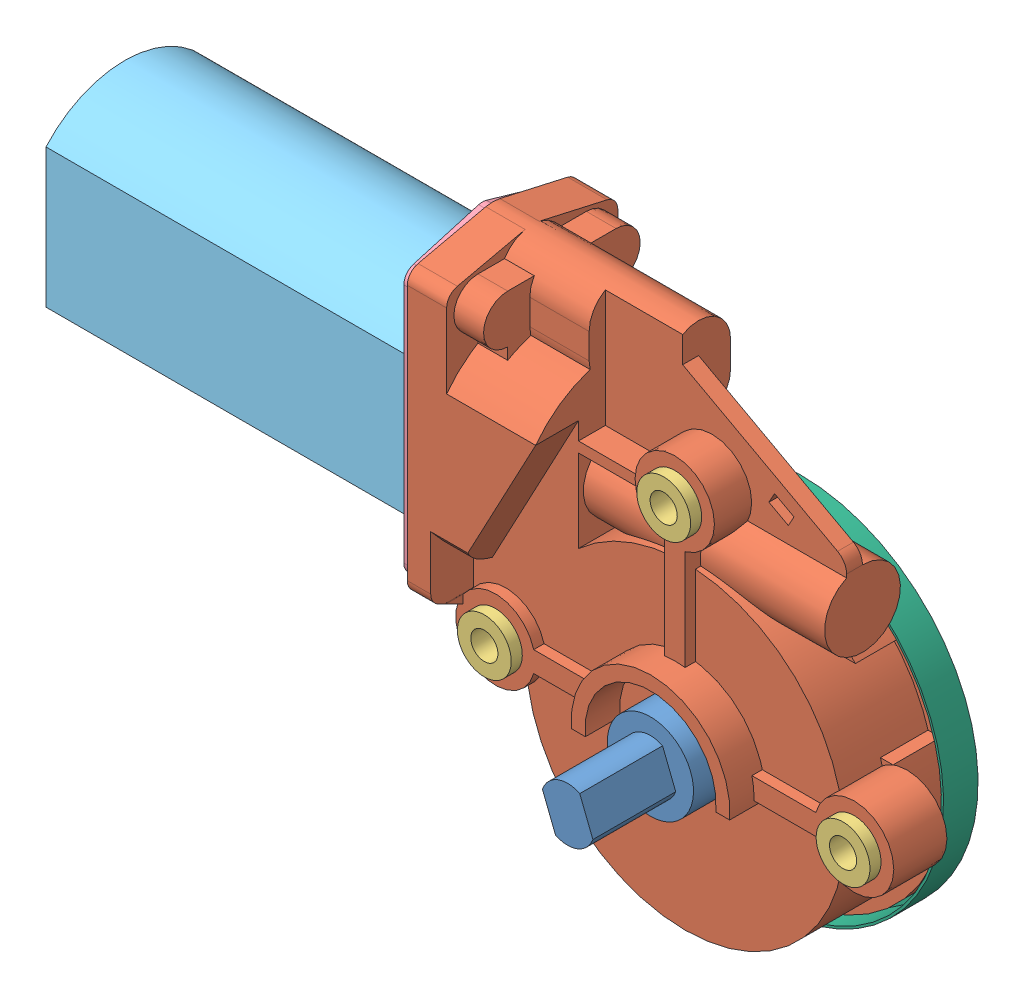
SolidWorks assembly Window Motor, configuration Default. Lengths in mm.
Overall size (163.83 107.48 45.24).
9 component instances, 6 part files, 13 mates.
Components (placement in the parent):
- Window Motor_Output Shaft-1: Window Motor_Output Shaft [Default] at (-98.1264 -79.6401 94.7009) x (0.930207 0.367035 0) z (0 0 1) size (15.85 15.85 21.62)
- Window Motor_Gearbox Housing-1: Window Motor_Gearbox Housing [Default] at (-98.1264 -79.6401 74.9905) size (83.55 92.74 31.5)
- Window Motor_Threaded Insert-1: Window Motor_Threaded Insert [Default] at (-98.1264 -39.65 74.9905) x (-0.364272 0.931293 0) z (0 0 1) size (9.91 9.91 11.94)
- Window Motor_Motor-1: Window Motor_Motor [Default] at (-207.6651 -49.1115 18.7981) x (0 0 1) z (-1 0 0) size (28.96 59.84 74.35)
  - Window Motor_Motor2-1: Window Motor_Motor2 [Default] at (46.4134 0 -0.4583) size (28.96 59.84 1.91)
  - Window Motor_Motor1-1: Window Motor_Motor1 [Default] at (46.4134 0.0469 1.4467) size (28.96 38.61 72.44)
- Window Motor_Threaded Insert-2: Window Motor_Threaded Insert [Default] at (-131.1264 -78.1401 74.9905) x (0.847447 0.53088 0) z (0 0 1) size (9.91 9.91 11.94)
- Window Motor_Threaded Insert-3: Window Motor_Threaded Insert [Default] at (-65.1264 -78.1401 74.9905) x (0.372744 0.927934 0) z (0 0 1) size (9.91 9.91 11.94)
- Window Motor_Gear Cap-1: Window Motor_Gear Cap [Default] at (-98.1264 -79.6401 52.6385) x (0.693865 0.720105 0) z (0 0 1) size (65.41 65.41 6.35)
Mates (geometry in assembly coordinates):
- Coincident1: coincident anti-aligned: plane of Window Motor_Gearbox Housing-1 through (-141.3699 -103.4538 65.2115) normal (-1 0 0); plane of Window Motor_Motor-1/Window Motor_Motor2-1 through (-141.3699 -49.2385 13.2898) normal (1 0 0)
- Width1: width aligned: plane of Window Motor_Gearbox Housing-1 through (-141.3699 -103.4538 49.4635) normal (0 0 -1); plane of Window Motor_Gearbox Housing-1 through (-141.3699 -103.4538 80.9595) normal (0 0 1); plane of Window Motor_Motor-1/Window Motor_Motor2-1 through (-143.2749 -49.2385 50.7335) normal (0 0 -1); plane of Window Motor_Motor-1/Window Motor_Motor2-1 through (-143.2749 -49.2385 79.6895) normal (0 0 1)
- Distance1: distance = 1.016 mm aligned: plane of Window Motor_Motor-1/Window Motor_Motor2-1 through (-143.2749 -79.2105 13.2898) normal (0 -1 0); plane of Window Motor_Gearbox Housing-1 through (-134.1309 -80.2265 65.2115) normal (0 -1 0)
- Concentric2: concentric aligned: cylinder of Window Motor_Gearbox Housing-1 through (-98.1264 -39.65 65.2115) axis (0 0 1) radius 2.54; cylinder of Window Motor_Threaded Insert-1 through (-98.1264 -39.65 65.0845) axis (0 0 1) radius 3.175
- Coincident4: coincident anti-aligned: plane of Window Motor_Gearbox Housing-1 through (-98.796 -136.935 74.9905) normal (0 0 1); plane of Window Motor_Threaded Insert-1 through (-98.1264 -39.65 74.9905) normal (0 0 -1)
- Concentric3: concentric anti-aligned: circle of Window Motor_Gearbox Housing-1; cylinder of Window Motor_Threaded Insert-2 through (-131.1264 -78.1401 65.0845) axis (0 0 1) radius 3.175
- Coincident5: coincident anti-aligned: plane of Window Motor_Gearbox Housing-1 through (-98.796 -136.935 74.9905) normal (0 0 1); plane of Window Motor_Threaded Insert-2 through (-131.1264 -78.1401 74.9905) normal (0 0 -1)
- Coincident7: coincident anti-aligned: plane of Window Motor_Gearbox Housing-1 through (-98.1264 -79.6401 52.6385) normal (0 0 -1); plane of Window Motor_Gear Cap-1 through (-98.1264 -79.6401 52.6385) normal (0 0 1)
- Concentric4: concentric aligned: cylinder of Window Motor_Gearbox Housing-1 through (-98.1264 -79.6401 131.48) axis (0 0 -1) radius 31.496; cylinder of Window Motor_Gear Cap-1 through (-98.1264 -79.6401 58.2265) axis (0 0 -1) radius 32.2961
- Concentric5: concentric aligned: cylinder of Window Motor_Output Shaft-1 through (-98.1264 -79.6401 73.0855) axis (0 0 1) radius 7.9248; cylinder of Window Motor_Gearbox Housing-1 through (-98.1264 -79.6401 52.6385) axis (0 0 1) radius 5.461
- Coincident8: coincident anti-aligned: plane of Window Motor_Output Shaft-1 through (-98.1264 -79.6401 73.0855) normal (0 0 -1); plane of Window Motor_Gearbox Housing-1 through (-98.1264 -79.6401 73.0855) normal (0 0 1)
- Concentric6: concentric aligned: cylinder of Window Motor_Gearbox Housing-1 through (-65.1264 -78.1401 65.2115) axis (0 0 1) radius 2.54; cylinder of Window Motor_Threaded Insert-3 through (-65.1264 -78.1401 65.0845) axis (0 0 1) radius 3.175
- Coincident9: coincident anti-aligned: plane of Window Motor_Gearbox Housing-1 through (-98.796 -136.935 74.9905) normal (0 0 1); plane of Window Motor_Threaded Insert-3 through (-65.1264 -78.1401 74.9905) normal (0 0 -1)
